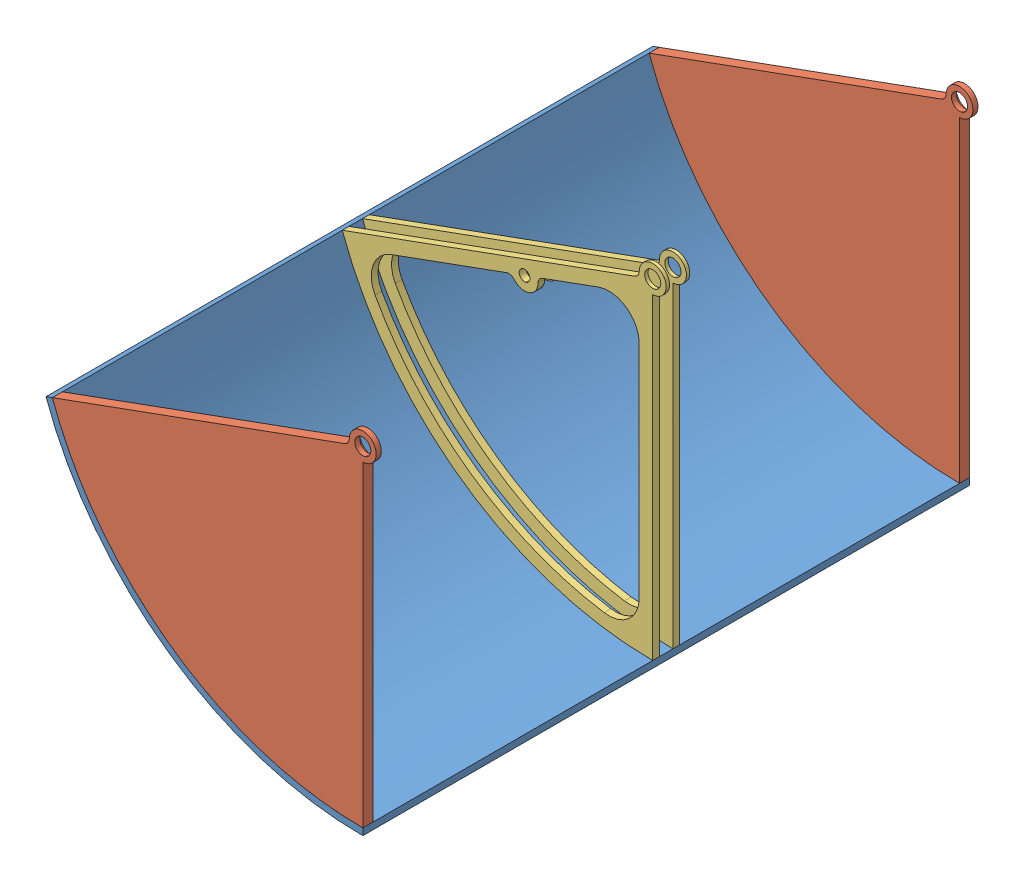
SolidWorks assembly lyzka spaw, configuration Domyślna. Lengths in mm.
Overall size (489.85 520 900).
5 component instances, 3 part files, 12 mates.
Components (placement in the parent):
- skorupa-1: skorupa [Domyślna] at (203.1583 270.4981 -382.5) size (469.85 332.41 900)
- bok-1: bok [Domyślna] at (203.1583 270.4981 502.5) size (480.45 510 15)
- bok-2: bok [Domyślna] at (203.1583 270.4981 -382.5) size (480.45 510 15)
- żebro-1: żebro [Domyślna] at (203.1583 270.4981 47.5) size (480.45 510 10)
- żebro-2: żebro [Domyślna] at (203.1583 270.4981 77.5) size (480.45 510 10)
Mates (geometry in assembly coordinates):
- Koncentryczne1: concentric aligned: cylinder of skorupa-1 through (203.1583 270.4981 517.5) axis (0 0 -1) radius 490; cylinder of bok-2 through (203.1583 270.4981 -367.5) axis (0 0 -1) radius 490
- Koncentryczne2: concentric aligned: cylinder of skorupa-1 through (203.1583 270.4981 517.5) axis (0 0 -1) radius 490; cylinder of żebro-1 through (203.1583 270.4981 57.5) axis (0 0 -1) radius 490
- Koncentryczne3: concentric aligned: cylinder of skorupa-1 through (203.1583 270.4981 517.5) axis (0 0 -1) radius 490; cylinder of bok-1 through (203.1583 270.4981 517.5) axis (0 0 -1) radius 490
- Koncentryczne4: concentric aligned: cylinder of skorupa-1 through (203.1583 270.4981 517.5) axis (0 0 -1) radius 490; cylinder of żebro-2 through (203.1583 270.4981 87.5) axis (0 0 -1) radius 490
- Wspólnie1: coincident aligned: plane of skorupa-1 through (203.1583 270.4981 -382.5) normal (0 0 -1); plane of bok-2 through (203.1583 270.4981 -382.5) normal (0 0 -1)
- Wspólnie2: coincident aligned: plane of skorupa-1 through (203.1583 270.4981 517.5) normal (0 0 1); plane of bok-1 through (203.1583 270.4981 517.5) normal (0 0 1)
- Wspólnie3: coincident aligned: plane of skorupa-1 through (-266.688 99.4881 517.5) normal (-0.34202 0.939693 0); plane of żebro-1 through (184.3644 263.6577 57.5) normal (-0.34202 0.939693 0)
- Wspólnie4: coincident aligned: plane of skorupa-1 through (-266.688 99.4881 517.5) normal (-0.34202 0.939693 0); plane of bok-2 through (184.3644 263.6577 -367.5) normal (-0.34202 0.939693 0)
- Wspólnie5: coincident aligned: plane of skorupa-1 through (-266.688 99.4881 517.5) normal (-0.34202 0.939693 0); plane of bok-1 through (184.3644 263.6577 517.5) normal (-0.34202 0.939693 0)
- Wspólnie6: coincident aligned: plane of skorupa-1 through (-266.688 99.4881 517.5) normal (-0.34202 0.939693 0); plane of żebro-2 through (184.3644 263.6577 87.5) normal (-0.34202 0.939693 0)
- Odległość1: distance = 415 mm anti-aligned: plane of bok-2 through (203.1583 270.4981 -367.5) normal (0 0 1); plane of żebro-1 through (203.1583 270.4981 47.5) normal (0 0 -1)
- Odległość2: distance = 415 mm anti-aligned: plane of żebro-2 through (203.1583 270.4981 87.5) normal (0 0 1); plane of bok-1 through (203.1583 270.4981 502.5) normal (0 0 -1)
